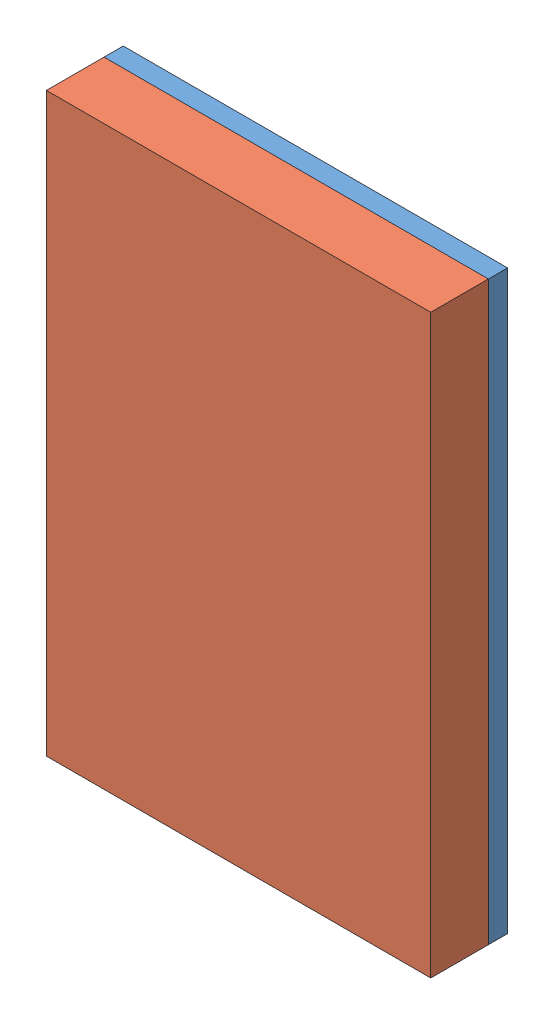
SolidWorks assembly spindle support, configuration Default. Lengths in mm.
Overall size (200 300 40).
3 component instances, 3 part files, 3 mates.
Components (placement in the parent):
- platform-1: platform [Default] at origin size (200 300 10)
- Part3-1: Part3 [Default] at (0 0 10) size (200 300 30)
- spindleBracket-1: spindleBracket [Default] at (129.3309 -197.9836 40) x (1 0 0) z (0 -1 0) size (121.25 30 170)
Mates (geometry in assembly coordinates):
- Coincident1: coincident anti-aligned: plane of platform-1 through (0 0 10) normal (0 0 1); plane of spindleBracket-1 through (129.3309 -197.9836 10) normal (0 0 -1)
- Parallel1: parallel aligned: plane of platform-1 through (0 0 10) normal (-1 0 0); plane of spindleBracket-1 through (41.6563 -197.9836 10) normal (-1 0 0)
- Parallel2: parallel aligned: plane of platform-1 through (0 0 10) normal (0 -1 0); plane of spindleBracket-1 through (129.3309 33.9542 10) normal (0 -1 0)
